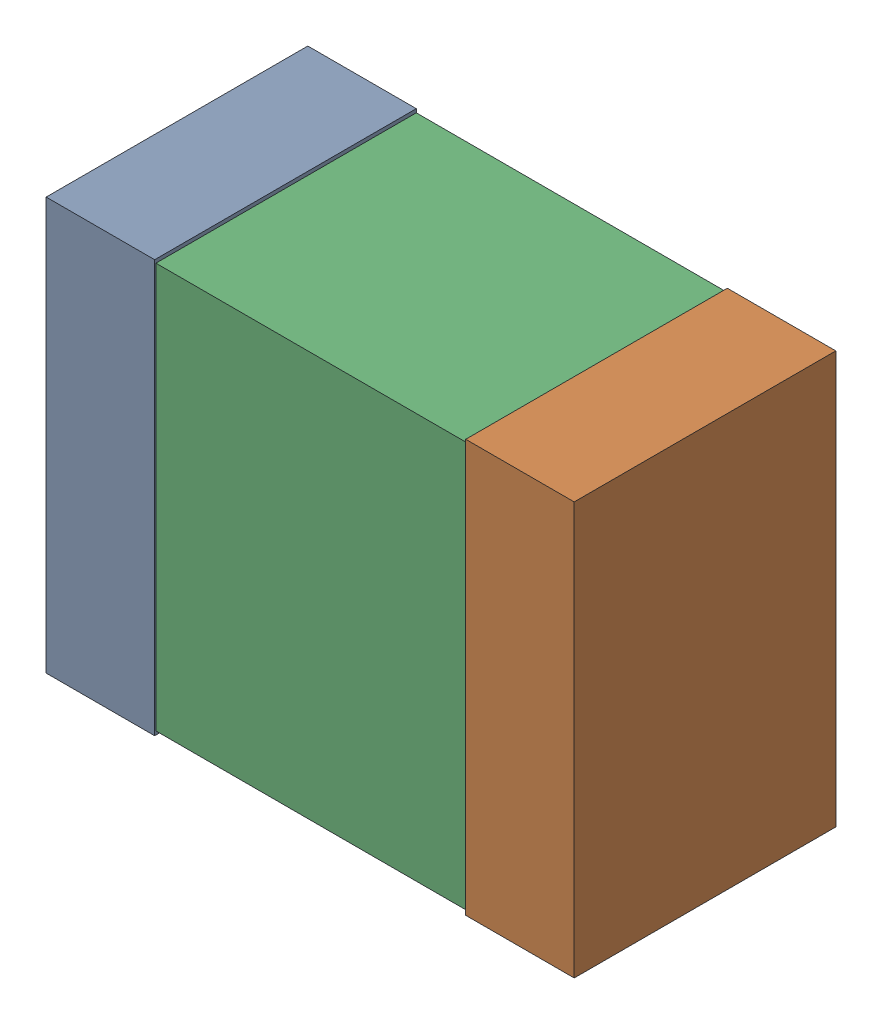
SolidWorks assembly C7_0Kanaloa_v2.0.0_Motor, configuration Default. Lengths in mm.
Overall size (3.65 2.85 1.81).
6 component instances, 2 part files, 0 mates.
Components (placement in the parent):
- 334788400-1: 334788400 [Default] at (59.51 56.642 0) size (0.75 2.85 1.81)
  - Extruded_5-1: Extruded_5 [Default] at origin size (0.75 2.85 1.81)
- 334788400-2: 334788400 [Default] at (62.41 56.642 0) size (0.75 2.85 1.81)
  - Extruded_5-1: Extruded_5 [Default] at origin size (0.75 2.85 1.81)
- 334788784-1: 334788784 [Default] at (60.96 56.642 0) size (3.6 2.8 1.8)
  - Extruded_6-1: Extruded_6 [Default] at origin size (3.6 2.8 1.8)
